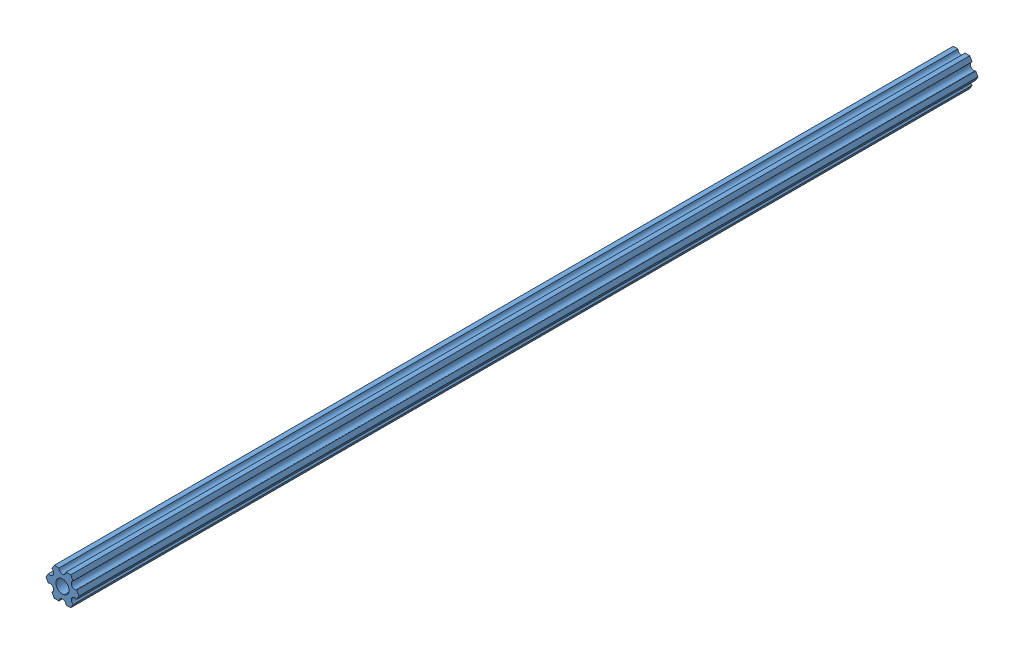
SolidWorks assembly Churro cross link and Screws, configuration Default. Lengths in mm.
Overall size (15.92 15.92 497.71).
3 component instances, 2 part files, 3 mates.
Components (placement in the parent):
- Churro 15750-1: Churro 15750 [Default] at (10.1799 23.1078 -21.0709) size (14.66 12.7 488.95)
- hex washer head tapping screw_ai-1: hex washer head tapping screw_ai [FHTS 0.25-20-G-0.75-C] at (10.1799 23.1078 382.1541) x (0 0 -1) z (1 0 0) size (24.64 12.19 12.19)
- hex washer head tapping screw_ai-2: hex washer head tapping screw_ai [FHTS 0.25-20-G-0.75-C] at (10.1799 23.1078 -24.2459) x (0 0 1) z (-0.381849 -0.924225 0) size (24.64 12.19 12.19)
Mates (geometry in assembly coordinates):
- Concentric77: concentric anti-aligned: cylinder of Churro 15750-1 through (10.1799 23.1078 467.8791) axis (0 0 -1) radius 2.9337; cylinder of hex washer head tapping screw_ai-1 through (10.1799 23.1078 382.1541) axis (0 0 1) radius 3.175
- Concentric76: concentric aligned: cylinder of Churro 15750-1 through (10.1799 23.1078 467.8791) axis (0 0 -1) radius 2.9337; cylinder of hex washer head tapping screw_ai-2 through (10.1799 23.1078 -24.2459) axis (0 0 -1) radius 3.175
- Distance2: distance = 3.175 mm anti-aligned: plane of Churro 15750-1 through (15.6791 26.2828 -21.0709) normal (0 0 -1); plane of hex washer head tapping screw_ai-2 through (7.2454 24.3202 -24.2459) normal (0 0 1)
